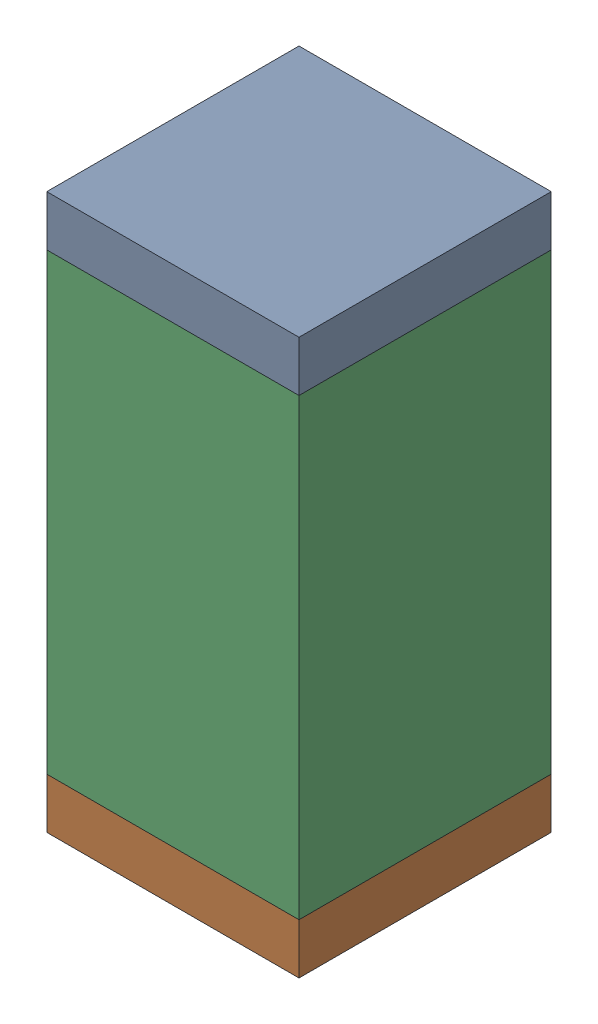
SolidWorks assembly R58, configuration Default. Lengths in mm.
Overall size (0.5 1.1 0.5).
6 component instances, 2 part files, 0 mates.
Components (placement in the parent):
- 810157360-1: 810157360 [Default] at (132.45 68.25 0) size (0.5 0.1 0.5)
  - Extruded_9-1: Extruded_9 [Default] at origin size (0.5 0.1 0.5)
- 810157360-2: 810157360 [Default] at (132.45 67.25 0) size (0.5 0.1 0.5)
  - Extruded_9-1: Extruded_9 [Default] at origin size (0.5 0.1 0.5)
- 791586336-1: 791586336 [Default] at (132.45 67.75 0) size (0.5 0.9 0.5)
  - Extruded_8-1: Extruded_8 [Default] at origin size (0.5 0.9 0.5)
